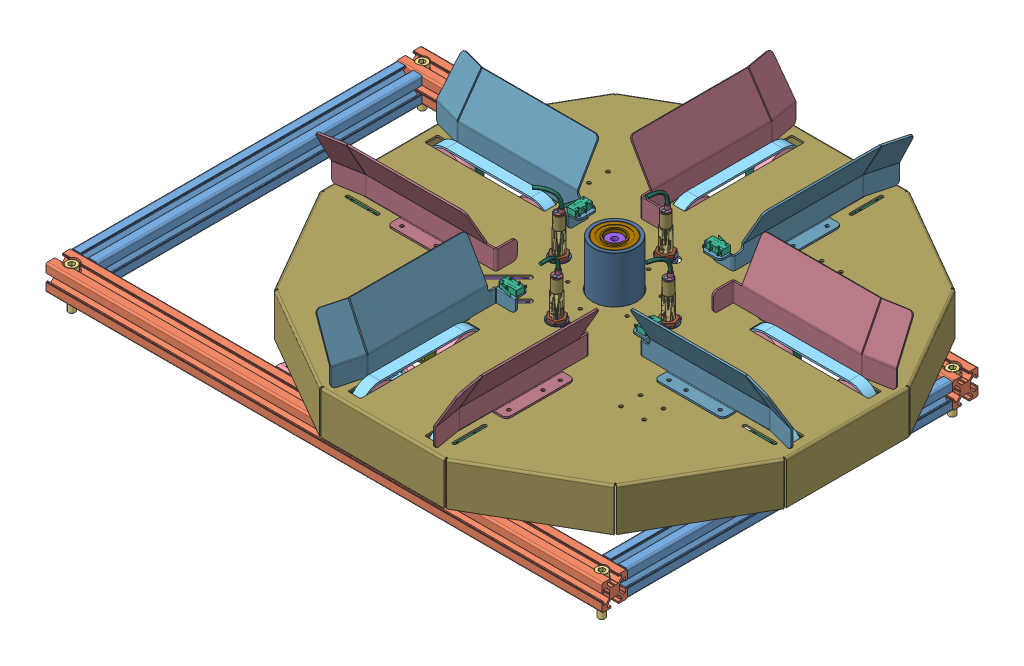
SolidWorks assembly Total_module, configuration Default. Lengths in mm.
Overall size (717 205.91 544).
158 component instances, 33 part files, 6 mates.
Components (placement in the parent):
- Frame-1: Frame [Default] at origin size (650 51 440)
  - Frame_profile_short-1: Frame_profile_short [Default] at origin size (30 30 380)
  - Frame_profile-1: Frame_profile [Default] at (-15 0 395) x (0 0 -1) z (1 0 0) size (30 30 650)
  - Frame_profile-2: Frame_profile [Default] at (635 0 -15) x (0 0 1) z (-1 0 0) size (30 30 650)
  - Frame_profile_short-2: Frame_profile_short [Default] at (620 0 0) size (30 30 380)
  - Frame_profile_short-3: Frame_profile_short [Default] at (470 0 0) size (30 30 380)
  - Frame_profile_short-4: Frame_profile_short [Default] at (390 0 0) size (30 30 380)
  - socket head cap screw_iso-10: socket head cap screw_iso [ISO 4762 M8 x 40 - 40N] at (0 14 -15) x (0 -1 0) z (0 0 1) size (48 13 13)
  - socket head cap screw_iso-11: socket head cap screw_iso [ISO 4762 M8 x 40 - 40N] at (0 14 395) x (0 -1 0) z (0.186343 0 0.982485) size (48 13 13)
  - socket head cap screw_iso-12: socket head cap screw_iso [ISO 4762 M8 x 40 - 40N] at (620 14 395) x (0 -1 0) z (0 0 1) size (48 13 13)
  - socket head cap screw_iso-13: socket head cap screw_iso [ISO 4762 M8 x 40 - 40N] at (620 14 -15) x (0 -1 0) z (0 0 1) size (48 13 13)
  - Converter_box-1: Converter_box [Default] at (289.5 -15 334) size (131 30 105)
  - Converter-1: Converter [00] at (257 -3.5 334) size (49 24 65)
  - Converter-2: Converter [00] at (322 -3.5 334) size (49 24 65)
- Rotation_mechanism-1: Rotation_mechanism [Default] at (430 15 190) size (182.99 140 182.98)
  - Foot-1: Foot [Default] at origin size (100 5 100)
  - Foot_bus-1: Foot_bus [Default] at (0 5 0) size (30 55 30)
  - Main_axis-1: Main_axis [Default] at (0 10 0) size (24 127 24)
  - taper roller bearing3_iso-1: taper roller bearing3_iso [ISO 355-3 - 3CC20 - 14,SI,NC,14] at (0 125 0) x (0 -1 0) z (-0.954411 0 -0.298495) size (15 42 42)
  - taper roller bearing3_iso-2: taper roller bearing3_iso [ISO 355-3 - 3CC20 - 14,SI,NC,14] at (0 62 0) x (0 -1 0) z (0 0 1) size (15 42 42)
  - Bearing_house_flange-1: Bearing_house_flange [Default] at (0 65 0) size (89 75 89)
  - Spur_gear_big-1: Spur_gear_big [Default] at (0 15 0) x (1 0 0) z (0 1 0) size (182.99 182.98 30)
- Carrousel-1: Carrousel [Default] at (430 101 190) size (544 150.11 544)
  - Main_disk-1: Main_disk [Default] at origin size (544 50 544)
  - Side_gide-1: Side_gide [Default] at (69.6317 2 196.1486) x (0 0 -1) z (1 0 0) size (186.64 68.84 54.68)
  - Side_gide-2: Side_gide [Default] at (196.1486 2 -69.6317) x (-1 0 0) z (0 0 -1) size (186.64 68.84 54.68)
  - Side_gide-3: Side_gide [Default] at (-69.6317 2 -196.1486) x (0 0 1) z (-1 0 0) size (186.64 68.84 54.68)
  - Side_gide-4: Side_gide [Default] at (-196.1486 2 69.6317) size (186.64 68.84 54.68)
  - Side_gide_sensor-1: Side_gide_sensor [Default] at (-196.1486 2 -69.6317) size (199.07 68.84 56.91)
  - Side_gide_sensor-2: Side_gide_sensor [Default] at (69.6317 2 -196.1486) x (0 0 1) z (-1 0 0) size (199.07 68.84 56.91)
  - Side_gide_sensor-3: Side_gide_sensor [Default] at (-69.6317 2 196.1486) x (0 0 -1) z (1 0 0) size (199.07 68.84 56.91)
  - Side_gide_sensor-4: Side_gide_sensor [Default] at (196.1486 2 69.6317) x (-1 0 0) z (0 0 -1) size (199.07 68.84 56.91)
  - Bearing_block-1: Bearing_block [Default] at (250.4627 -2 -57.5) x (-1 0 0) z (0 0 1) size (30 32 10)
  - Bearing_block-2: Bearing_block [Default] at (57.5 -2 -220.4627) x (0 0 -1) z (-1 0 0) size (30 32 10)
  - Bearing_block-3: Bearing_block [Default] at (-67.5 -2 -121.1486) x (0 0 -1) z (-1 0 0) size (30 32 10)
  - Bearing_block-4: Bearing_block [Default] at (-220.4627 -2 67.5) x (-1 0 0) z (0 0 1) size (30 32 10)
  - Bearing_block-5: Bearing_block [Default] at (57.5 -2 250.4627) x (0 0 -1) z (-1 0 0) size (30 32 10)
  - Bearing_block-6: Bearing_block [Default] at (-67.5 -2 250.4627) x (0 0 -1) z (-1 0 0) size (30 32 10)
  - Bearing_block-7: Bearing_block [Default] at (250.4627 -2 67.5) x (-1 0 0) z (0 0 1) size (30 32 10)
  - Bearing_block-8: Bearing_block [Default] at (57.5 -2 151.1486) x (0 0 -1) z (-1 0 0) size (30 32 10)
  - Bearing_block-9: Bearing_block [Default] at (-67.5 -2 -220.4627) x (0 0 -1) z (-1 0 0) size (30 32 10)
  - Bearing_block-10: Bearing_block [Default] at (-220.4627 -2 -57.5) x (-1 0 0) z (0 0 1) size (30 32 10)
  - Bearing_block-11: Bearing_block [Default] at (151.1486 -2 -57.5) x (-1 0 0) z (0 0 1) size (30 32 10)
  - Bearing_block-12: Bearing_block [Default] at (-121.1486 -2 67.5) x (-1 0 0) z (0 0 1) size (30 32 10)
  - Engine_mount-1: Engine_mount [Default] at (136.1486 -26 80) size (37 42.5 65)
  - Engine_mount-2: Engine_mount [Default] at (80 -26 -136.1486) x (0 0 -1) z (1 0 0) size (37 42.5 65)
  - Engine_mount-3: Engine_mount [Default] at (-80 -26 136.1486) x (0 0 1) z (-1 0 0) size (37 42.5 65)
  - Engine_mount-4: Engine_mount [Default] at (-136.1486 -26 -80) x (-1 0 0) z (0 0 -1) size (37 42.5 65)
  - Plain_bearing-1: Plain_bearing [Default] at (-136.1486 -19 69.5) x (1 0 0) z (0 1 0) size (16 8 16)
  - Plain_bearing-2: Plain_bearing [Default] at (235.4627 -19 -69.5) x (1 0 0) z (0 -1 0) size (16 8 16)
  - Plain_bearing-3: Plain_bearing [Default] at (136.1486 -19 -69.5) x (1 0 0) z (0 -1 0) size (16 8 16)
  - Plain_bearing-4: Plain_bearing [Default] at (69.5 -19 235.4627) x (0 1 0) z (0 0 1) size (16 8 16)
  - Plain_bearing-5: Plain_bearing [Default] at (-69.5 -19 -235.4627) x (0 -1 0) z (0 0 1) size (16 8 16)
  - Plain_bearing-6: Plain_bearing [Default] at (-235.4627 -19 69.5) x (1 0 0) z (0 1 0) size (16 8 16)
  - Plain_bearing-7: Plain_bearing [Default] at (-235.4627 -19 -69.5) x (1 0 0) z (0 -1 0) size (16 8 16)
  - Plain_bearing-8: Plain_bearing [Default] at (235.4627 -19 69.5) x (1 0 0) z (0 1 0) size (16 8 16)
  - Plain_bearing-9: Plain_bearing [Default] at (69.5 -19 -235.4627) x (0 1 0) z (0 0 1) size (16 8 16)
  - Plain_bearing-10: Plain_bearing [Default] at (-69.5 -19 235.4627) x (0 -1 0) z (0 0 1) size (16 8 16)
  - Plain_bearing-11: Plain_bearing [Default] at (69.5 -19 136.1486) x (0 1 0) z (0 0 1) size (16 8 16)
  - Plain_bearing-12: Plain_bearing [Default] at (-69.5 -19 -136.1486) x (0 -1 0) z (0 0 1) size (16 8 16)
  - Slide_axis-1: Slide_axis [Default] at (-82.5 -19 -235.4627) x (0 -0.940008 -0.341151) z (1 0 0) size (8 8 165)
  - Slide_axis-2: Slide_axis [Default] at (-235.4627 -19 -82.5) x (0.998743 0.050129 0) z (0 0 1) size (8 8 165)
  - Slide_axis-3: Slide_axis [Default] at (82.5 -19 235.4627) x (0 0.050129 0.998743) z (-1 0 0) size (8 8 165)
  - Slide_axis-4: Slide_axis [Default] at (235.4627 -19 -82.5) x (0.998743 0.050129 0) z (0 0 1) size (8 8 165)
  - Drive_axis-1: Drive_axis [Default] at (63.5 -19 -136.1486) x (0 -0.903748 0.428065) z (-1 0 0) size (8 8 145)
  - Drive_axis-2: Drive_axis [Default] at (-136.1486 -19 -63.5) x (-0.700893 -0.713266 0) z (0 0 1) size (8 8 145)
  - Drive_axis-3: Drive_axis [Default] at (-63.5 -19 136.1486) x (0 -0.987122 -0.159968) z (1 0 0) size (8 8 145)
  - Drive_axis-4: Drive_axis [Default] at (136.1486 -19 63.5) x (-0.80966 -0.586899 0) z (0 0 -1) size (8 8 145)
  - Adapter_drive_axis-2: Adapter_drive_axis [Default] at (51 -19 -136.1486) x (0 -0.997824 0.065928) z (0 0.065928 0.997824) size (14 25 14)
  - Adapter_drive_axis-3: Adapter_drive_axis [Default] at (-136.1486 -19 -51) x (0.065928 -0.997824 0) z (0.997824 0.065928 0) size (14 25 14)
  - Adapter_drive_axis-4: Adapter_drive_axis [Default] at (-51 -19 136.1486) x (0 0.899601 0.436712) z (0 -0.436712 0.899601) size (14 25 14)
  - Adapter_drive_axis-5: Adapter_drive_axis [Default] at (136.1486 -19 51) x (0.142486 -0.989797 0) z (-0.989797 -0.142486 0) size (14 25 14)
  - DC_drive-4: DC_drive [Default] at (85 -26.0005 -136.1486) x (0 0 -1) z (1 0 0) size (37 37 79.5)
  - DC_drive-5: DC_drive [Default] at (-136.1486 -26.0005 -85) x (-1 0 0) z (0 0 -1) size (37 37 79.5)
  - DC_drive-6: DC_drive [Default] at (-85 -26.0005 136.1486) x (0 0 1) z (-1 0 0) size (37 37 79.5)
  - DC_drive-7: DC_drive [Default] at (136.1486 -26.0005 85) size (37 37 79.5)
  - Timing_belt_pully-1: Timing_belt_pully [Default] at (-45 -19 -235.4627) x (1 0 0) z (0 0.001991 0.999998) size (21 45 45)
  - Timing_belt_pully-6: Timing_belt_pully [Default] at (45 -19 -235.4627) x (-1 0 0) z (0 -0.923463 -0.383688) size (21 45 45)
  - Timing_belt_pully-7: Timing_belt_pully [Default] at (-45 -19 -136.1486) x (1 0 0) z (0 0.001991 0.999998) size (21 45 45)
  - Timing_belt_pully-8: Timing_belt_pully [Default] at (45 -19 -136.1486) x (-1 0 0) z (0 -0.311973 -0.950091) size (21 45 45)
  - Timing_belt_pully-9: Timing_belt_pully [Default] at (-235.4627 -19 -45) x (0 0 1) z (-0.383688 -0.923463 0) size (21 45 45)
  - Timing_belt_pully-10: Timing_belt_pully [Default] at (-235.4627 -19 45) x (0 0 -1) z (0.708155 -0.706057 0) size (21 45 45)
  - Timing_belt_pully-11: Timing_belt_pully [Default] at (-136.1486 -19 -45) x (0 0 1) z (-0.383688 -0.923463 0) size (21 45 45)
  - Timing_belt_pully-12: Timing_belt_pully [Default] at (-136.1486 -19 45) x (0 0 -1) z (0.708155 -0.706057 0) size (21 45 45)
  - Timing_belt_pully-13: Timing_belt_pully [Default] at (-45 -19 235.4627) x (1 0 0) z (0 0.384887 0.922964) size (21 45 45)
  - Timing_belt_pully-15: Timing_belt_pully [Default] at (45 -19 235.4627) x (-1 0 0) z (0 -0.706057 -0.708155) size (21 45 45)
  - Timing_belt_pully-16: Timing_belt_pully [Default] at (-45 -19 136.1486) x (1 0 0) z (0 0.384887 0.922964) size (21 45 45)
  - Timing_belt_pully-17: Timing_belt_pully [Default] at (45 -19 136.1486) x (-1 0 0) z (0 -0.706057 -0.708155) size (21 45 45)
  - Timing_belt_pully-18: Timing_belt_pully [Default] at (235.4627 -19 45) x (0 0 -1) z (0.924597 -0.380946 0) size (21 45 45)
  - Timing_belt_pully-19: Timing_belt_pully [Default] at (235.4627 -19 -45) x (0 0 1) z (-0.708155 -0.706057 0) size (21 45 45)
  - Timing_belt_pully-20: Timing_belt_pully [Default] at (136.1486 -19 45) x (0 0 -1) z (0.852579 -0.522598 0) size (21 45 45)
  - Timing_belt_pully-21: Timing_belt_pully [Default] at (136.1486 -19 -45) x (0 0 1) z (-0.802504 -0.596646 0) size (21 45 45)
  - Belt2-4^Carrousel-1: Belt2-4^Carrousel [Default] at (136.1486 -19 45) size (148.31 49 13) (virtual)
  - Belt2-4^Carrousel-2: Belt2-4^Carrousel [Default] at (235.4627 -19 -45) x (-1 0 0) z (0 0 1) size (148.31 49 13) (virtual)
  - Belt2-4^Carrousel-3: Belt2-4^Carrousel [Default] at (45 -19 -235.4627) x (0 0 1) z (-1 0 0) size (148.31 49 13) (virtual)
  - Belt2-4^Carrousel-4: Belt2-4^Carrousel [Default] at (-45 -19 -235.4627) x (0 0 1) z (1 0 0) size (148.31 49 13) (virtual)
  - Belt2-4^Carrousel-5: Belt2-4^Carrousel [Default] at (-136.1486 -19 -45) x (-1 0 0) z (0 0 1) size (148.31 49 13) (virtual)
  - Belt2-4^Carrousel-6: Belt2-4^Carrousel [Default] at (-235.4627 -19 45) size (148.31 49 13) (virtual)
  - Belt2-4^Carrousel-7: Belt2-4^Carrousel [Default] at (-45 -19 235.4627) x (0 0 -1) z (-1 0 0) size (148.31 49 13) (virtual)
  - Belt2-4^Carrousel-8: Belt2-4^Carrousel [Default] at (45 -19 235.4627) x (0 0 -1) z (-1 0 0) size (148.31 49 13) (virtual)
  - Limit_switch-2: Limit_switch [Default] at (-85.2778 26.1366 -49.6317) x (0 0 1) z (1 0 0) size (20 6.44 19.27)
  - Limit_switch-3: Limit_switch [Default] at (-49.6317 26.1366 85.2778) x (1 0 0) z (0 0 -1) size (20 6.44 19.27)
  - Limit_switch-4: Limit_switch [Default] at (85.2778 26.1366 49.6317) x (0 0 -1) z (-1 0 0) size (20 6.44 19.27)
  - Limit_switch-5: Limit_switch [Default] at (49.6317 26.1366 -85.2778) x (-1 0 0) z (0 0 1) size (20 6.44 19.27)
  - Adjusting_ring-1: Adjusting_ring [Default] at (-74.5 -19 -235.4627) x (1 0 0) z (0 0.049273 0.998785) size (10 18 18)
  - Adjusting_ring-2: Adjusting_ring [Default] at (-74.5 -19 -136.1486) x (1 0 0) z (0 0.049273 0.998785) size (10 18 18)
  - Adjusting_ring-3: Adjusting_ring [Default] at (74.5 -19 -235.4627) x (-1 0 0) z (0 -0.904287 -0.426925) size (10 18 18)
  - Adjusting_ring-4: Adjusting_ring [Default] at (-235.4627 -19 -74.5) x (0 0 -1) z (0.998785 0.049273 0) size (10 18 18)
  - Adjusting_ring-5: Adjusting_ring [Default] at (-235.4627 -19 74.5) x (0 0 -1) z (0.998785 0.049273 0) size (10 18 18)
  - Adjusting_ring-6: Adjusting_ring [Default] at (-136.1486 -19 74.5) x (0 0 -1) z (0.998785 0.049273 0) size (10 18 18)
  - Adjusting_ring-7: Adjusting_ring [Default] at (74.5 -19 136.1486) x (-1 0 0) z (0 0.049273 -0.998785) size (10 18 18)
  - Adjusting_ring-8: Adjusting_ring [Default] at (74.5 -19 235.4627) x (1 0 0) z (0 0.941917 0.335846) size (10 18 18)
  - Adjusting_ring-9: Adjusting_ring [Default] at (-74.5 -19 235.4627) x (1 0 0) z (0 0.941917 0.335846) size (10 18 18)
  - Adjusting_ring-10: Adjusting_ring [Default] at (235.4627 -19 74.5) x (0 0 -1) z (0.335846 0.941917 0) size (10 18 18)
  - Adjusting_ring-11: Adjusting_ring [Default] at (235.4627 -19 -74.5) x (0 0 -1) z (0.335846 0.941917 0) size (10 18 18)
  - Adjusting_ring-12: Adjusting_ring [Default] at (136.1486 -19 -76.7431) x (0 0 1) z (-0.671031 0.741429 0) size (10 18 18)
  - Stepper_drive_nema23-1: Stepper_drive_nema23 [Predeterminado] at (-109.2122 -56.6 69.3314) x (0.707107 0 -0.707107) z (0 -1 0) size (56.56 56.56 75.8)
  - Spur_gear_small-1: Spur_gear_small [Default] at (-69.3314 -69.2 69.3314) x (-0.837169 0 -0.546944) z (0 1 0) size (25 25 20)
  - Inductive_sensor-1: Inductive_sensor [Default] at (-65 -16 0) x (0.630141 0 0.776481) z (0 -1 0) size (20.5 32.31 86.91)
    - LJ12A3-4-Z_BX v6.step-1: LJ12A3-4-Z_BX v6.step [Default] at origin size (20.5 32.31 86.91)
      - 93925A300.step-1: 93925A300.step [Default] at (-0.0005 -0.0003 -11.5) x (1 0 0) z (0 0 -1) size (20.5 20.5 2.11)
      - 93925A300.step-2: 93925A300.step [Default] at (-0.0006 -0.0007 -16.5) x (1 0 0) z (0 0 -1) size (20.5 20.5 2.11)
      - Nut.step-1: Nut.step [Default] at (-0.0001 -0.0008 -11) size (19.14 16.74 3.53)
      - Nut.step-2: Nut.step [Default] at (-0.0004 -0.0002 -17) x (1 0 0) z (0 0 -1) size (19.14 16.74 3.53)
      - LJ12A3-4-Z_BX.step-1: LJ12A3-4-Z_BX.step [Default] at origin size (13.73 13.36 60)
      - LJ12A3-4-Z_BX-0.step-1: LJ12A3-4-Z_BX-0.step [Default] at origin size (10.5 10.5 6.2)
      - LJ12A3-4-Z_BX-1.step-1: LJ12A3-4-Z_BX-1.step [Default] at origin size (3.5 3.5 1.5)
      - LJ12A3-4-Z_BX-2.step-1: LJ12A3-4-Z_BX-2.step [Default] at origin size (3.54 25.97 25.31)
  - Inductive_sensor-2: Inductive_sensor [Default] at (-2.6585 -16 64.9456) x (0.99014 0 -0.140078) z (0 -1 0) size (20.5 32.31 86.91)
    - LJ12A3-4-Z_BX v6.step-1: LJ12A3-4-Z_BX v6.step [Default] at origin size (20.5 32.31 86.91)
      - 93925A300.step-1: 93925A300.step [Default] at (-0.0005 -0.0003 -11.5) x (1 0 0) z (0 0 -1) size (20.5 20.5 2.11)
      - 93925A300.step-2: 93925A300.step [Default] at (-0.0006 -0.0007 -16.5) x (1 0 0) z (0 0 -1) size (20.5 20.5 2.11)
      - Nut.step-1: Nut.step [Default] at (-0.0001 -0.0008 -11) size (19.14 16.74 3.53)
      - Nut.step-2: Nut.step [Default] at (-0.0004 -0.0002 -17) x (1 0 0) z (0 0 -1) size (19.14 16.74 3.53)
      - LJ12A3-4-Z_BX.step-1: LJ12A3-4-Z_BX.step [Default] at origin size (13.73 13.36 60)
      - LJ12A3-4-Z_BX-0.step-1: LJ12A3-4-Z_BX-0.step [Default] at origin size (10.5 10.5 6.2)
      - LJ12A3-4-Z_BX-1.step-1: LJ12A3-4-Z_BX-1.step [Default] at origin size (3.5 3.5 1.5)
      - LJ12A3-4-Z_BX-2.step-1: LJ12A3-4-Z_BX-2.step [Default] at origin size (3.54 25.97 25.31)
  - Inductive_sensor-3: Inductive_sensor [Default] at (64.9712 -16 1.9362) x (0.982641 0 0.185518) z (0 -1 0) size (20.5 32.31 86.91)
    - LJ12A3-4-Z_BX v6.step-1: LJ12A3-4-Z_BX v6.step [Default] at origin size (20.5 32.31 86.91)
      - 93925A300.step-1: 93925A300.step [Default] at (-0.0005 -0.0003 -11.5) x (1 0 0) z (0 0 -1) size (20.5 20.5 2.11)
      - 93925A300.step-2: 93925A300.step [Default] at (-0.0006 -0.0007 -16.5) x (1 0 0) z (0 0 -1) size (20.5 20.5 2.11)
      - Nut.step-1: Nut.step [Default] at (-0.0001 -0.0008 -11) size (19.14 16.74 3.53)
      - Nut.step-2: Nut.step [Default] at (-0.0004 -0.0002 -17) x (1 0 0) z (0 0 -1) size (19.14 16.74 3.53)
      - LJ12A3-4-Z_BX.step-1: LJ12A3-4-Z_BX.step [Default] at origin size (13.73 13.36 60)
      - LJ12A3-4-Z_BX-0.step-1: LJ12A3-4-Z_BX-0.step [Default] at origin size (10.5 10.5 6.2)
      - LJ12A3-4-Z_BX-1.step-1: LJ12A3-4-Z_BX-1.step [Default] at origin size (3.5 3.5 1.5)
      - LJ12A3-4-Z_BX-2.step-1: LJ12A3-4-Z_BX-2.step [Default] at origin size (3.54 25.97 25.31)
  - Inductive_sensor-4: Inductive_sensor [Default] at (-5 -16 -64.8074) x (1 0 0) z (0 -1 0) size (20.5 32.31 86.91)
    - LJ12A3-4-Z_BX v6.step-1: LJ12A3-4-Z_BX v6.step [Default] at origin size (20.5 32.31 86.91)
      - 93925A300.step-1: 93925A300.step [Default] at (-0.0005 -0.0003 -11.5) x (1 0 0) z (0 0 -1) size (20.5 20.5 2.11)
      - 93925A300.step-2: 93925A300.step [Default] at (-0.0006 -0.0007 -16.5) x (1 0 0) z (0 0 -1) size (20.5 20.5 2.11)
      - Nut.step-1: Nut.step [Default] at (-0.0001 -0.0008 -11) size (19.14 16.74 3.53)
      - Nut.step-2: Nut.step [Default] at (-0.0004 -0.0002 -17) x (1 0 0) z (0 0 -1) size (19.14 16.74 3.53)
      - LJ12A3-4-Z_BX.step-1: LJ12A3-4-Z_BX.step [Default] at origin size (13.73 13.36 60)
      - LJ12A3-4-Z_BX-0.step-1: LJ12A3-4-Z_BX-0.step [Default] at origin size (10.5 10.5 6.2)
      - LJ12A3-4-Z_BX-1.step-1: LJ12A3-4-Z_BX-1.step [Default] at origin size (3.5 3.5 1.5)
      - LJ12A3-4-Z_BX-2.step-1: LJ12A3-4-Z_BX-2.step [Default] at origin size (3.54 25.97 25.31)
Mates (geometry in assembly coordinates):
- Coincident1: coincident: plane of Frame-1/Frame_profile_short-3 through (483 15 380) normal (0 1 0); plane of Rotation_mechanism-1/Foot-1 through (430 15 190) normal (0 -1 0)
- Distance1: distance = 5 mm: plane of Rotation_mechanism-1/Foot-1 through (480 20 240) normal (1 0 0); plane of Frame-1/Frame_profile_short-3 through (485 4.8 380) normal (1 0 0)
- Distance2: distance = 140 mm: plane of Rotation_mechanism-1/Foot-1 through (480 20 240) normal (0 0 1); plane of Frame-1/Frame_profile-1 through (635 4.8 380) normal (0 0 -1)
- Concentric1: concentric: cylinder of Rotation_mechanism-1/Bearing_house_flange-1 through (430 -920.2373 190) axis (0 -1 0) radius 25; cylinder of Carrousel-1/Main_disk-1 through (430 51 190) axis (0 1 0) radius 26
- Coincident4: coincident: plane of Rotation_mechanism-1/Bearing_house_flange-1 through (430 99 165) normal (0 1 0); plane of Carrousel-1/Main_disk-1 through (430 99 190) normal (0 -1 0)
- Concentric2: concentric: cylinder of Rotation_mechanism-1/Bearing_house_flange-1 through (395.359 80 170) axis (0 1 0) radius 2; cylinder of Carrousel-1/Main_disk-1 through (395.359 51 170) axis (0 1 0) radius 2
